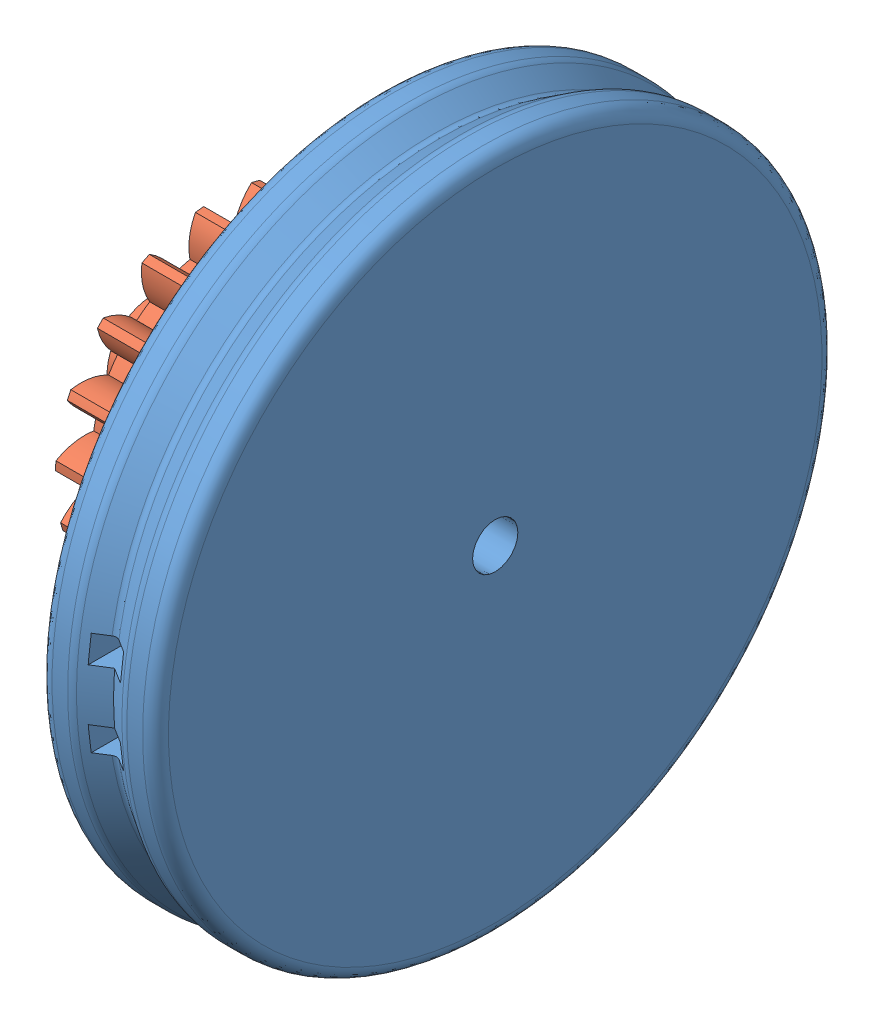
SolidWorks assembly GearPulleyV1_LC, configuration Default. Lengths in mm.
Overall size (53 105 105).
2 component instances, 2 part files, 4 mates.
Components (placement in the parent):
- NouvellePulleyModulaire-1: NouvellePulleyModulaire [Default] x (0 -1 0) z (-1 0 0) size (105 105 18)
- GearFil_V6_LC-1: GearFil_V6_LC [Défaut] at (140.8097 714.8225 -376.7903) x (1 0 0) z (0 0.83093 -0.556377) size (35 49.45 50)
Mates (geometry in assembly coordinates):
- Coincident5: coincident anti-aligned: plane of NouvellePulleyModulaire-1 through (0 0 0) normal (-1 0 0)
- Coincident6: coincident anti-aligned: plane of NouvellePulleyModulaire-1 through (0 0 0) normal (0 -1 0)
- Coincident7: coincident aligned: plane of NouvellePulleyModulaire-1 through (0 0 0) normal (0 0 1)
- Coincident8: coincident aligned: circle of NouvellePulleyModulaire-1; circle of GearFil_V6_LC-1
